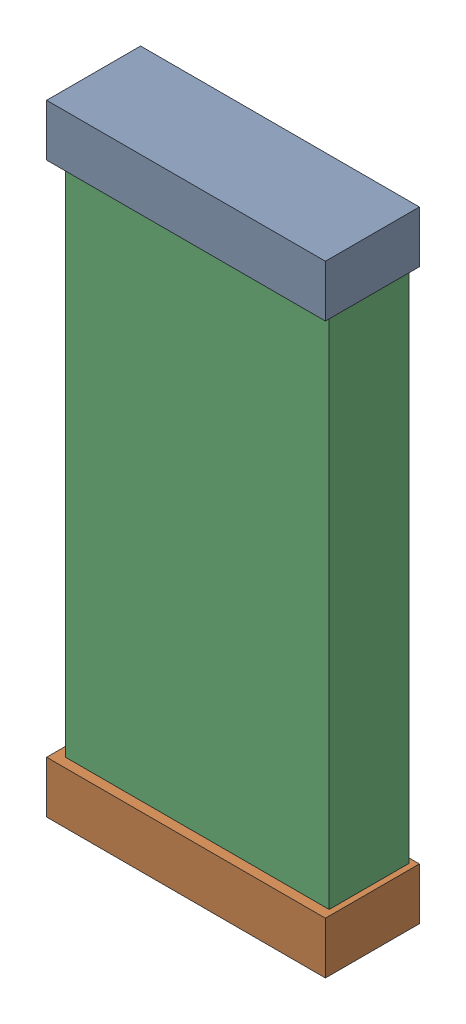
SolidWorks assembly C3, configuration Default. Lengths in mm.
Overall size (1.48 3.3 0.5).
6 component instances, 2 part files, 0 mates.
Components (placement in the parent):
- 744579568-1: 744579568 [Default] at (28.2899 14.6101 0.001) size (1.48 0.28 0.5)
  - Extruded (21)-1: Extruded (21) [Default] at origin size (1.48 0.28 0.5)
- 744579568_1-1: 744579568_1 [Default] at (28.2899 11.5899 0.001) size (1.48 0.28 0.5)
  - Extruded (21)-1: Extruded (21) [Default] at origin size (1.48 0.28 0.5)
- 744579440-1: 744579440 [Default] at (28.3 13.085 0.025) size (1.4 3.27 0.42)
  - Extruded (22)-1: Extruded (22) [Default] at origin size (1.4 3.27 0.42)
